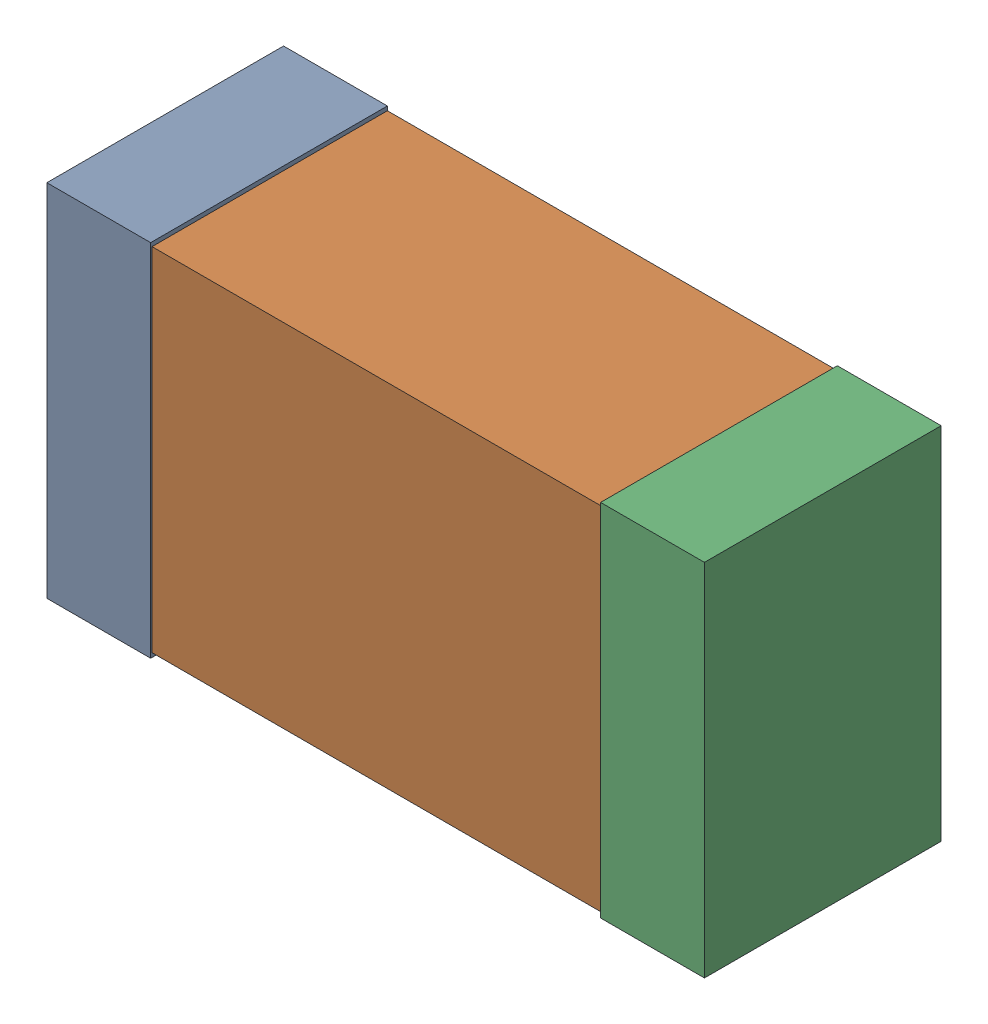
SolidWorks assembly C9_Motor_11Kanaloa_v2.0.0_Motor, configuration Default. Lengths in mm.
Overall size (2.38 1.3 0.85).
6 component instances, 2 part files, 0 mates.
Components (placement in the parent):
- 352877648-1: 352877648 [Default] at (119.353 161.036 0) size (0.38 1.3 0.85)
  - Extruded_14-1: Extruded_14 [Default] at origin size (0.38 1.3 0.85)
- 352877392-1: 352877392 [Default] at (120.353 161.036 0) size (2.2 1.27 0.85)
  - Extruded_15-1: Extruded_15 [Default] at origin size (2.2 1.27 0.85)
- 352877648-2: 352877648 [Default] at (121.353 161.036 0) size (0.38 1.3 0.85)
  - Extruded_14-1: Extruded_14 [Default] at origin size (0.38 1.3 0.85)
